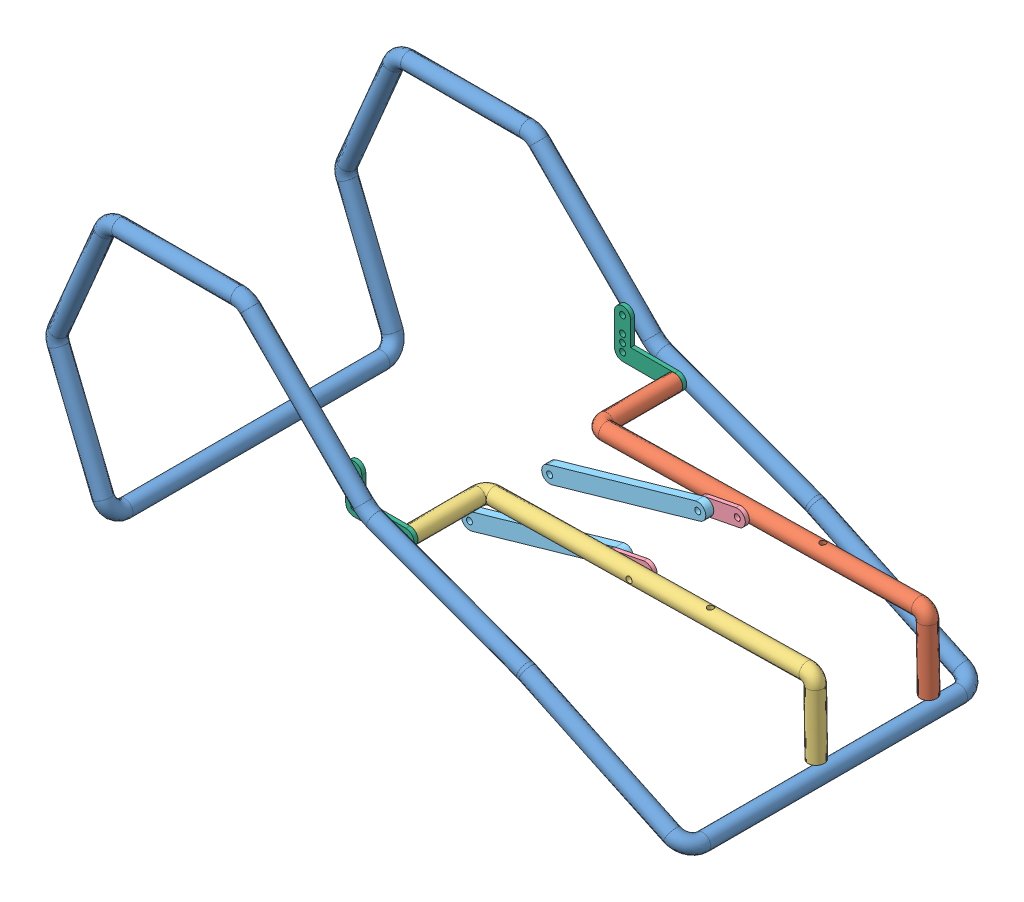
SolidWorks assembly Prototype, configuration Default. Lengths in mm.
Overall size (1087.11 431.8 482.6).
9 component instances, 6 part files, 26 mates.
Components (placement in the parent):
- Nubax Trio Frame-1: Nubax Trio Frame [Default] at (-437.8534 -203.7386 240.4024) size (1021.84 431.8 482.6)
- Support-2: Support [Default] at (19.3466 -9.1379 -197.7476) x (0.99987 0.016133 0) z (0 0 -1) size (546.1 127 133.35)
- Support 2-1: Support 2 [Default] at (19.3466 -9.1379 221.3524) x (0.99987 0.016133 0) z (0 0 1) size (546.1 127 133.35)
- Coupler-1: Coupler [Default] at (233.1407 -10.1249 81.6524) x (0.981686 0.190509 0) z (0 0 1) size (76.2 25.4 6.35)
- Coupler-2: Coupler [Default] at (233.1407 -10.1249 -64.3976) x (0.981686 0.190509 0) z (0 0 1) size (76.2 25.4 6.35)
- Rocker1-1: Rocker1 [Default] at (91.0226 -48.6174 -58.0476) x (0.27603 -0.961149 0) z (0 0 1) size (25.4 269.24 12.7)
- Rocker1-2: Rocker1 [Default] at (91.0226 -48.6174 68.9524) x (0.27603 -0.961149 0) z (0 0 1) size (25.4 269.24 12.7)
- Ground link support-1: Ground link support [Default] at (19.3466 -9.1379 221.3524) size (107.95 76.2 6.35)
- Ground link support-2: Ground link support [Default] at (19.3466 -9.1379 -204.0976) size (107.95 76.2 6.35)
Mates (geometry in assembly coordinates):
- Concentric2: concentric anti-aligned: cylinder of Nubax Trio Frame-1 through (19.3466 -9.1379 240.4024) axis (0 0 1) radius 4.7625; cylinder of Support-2 through (19.3466 -9.1379 -197.7476) axis (0 0 -1) radius 4.7625
- Concentric3: concentric aligned: cylinder of Nubax Trio Frame-1 through (19.3466 -9.1379 240.4024) axis (0 0 1) radius 4.7625; cylinder of Support 2-1 through (19.3466 -9.1379 221.3524) axis (0 0 1) radius 4.7625
- Coincident1: coincident aligned: plane of Support-2 through (541.8228 -115.0226 -77.0976) normal (0.016133 -0.99987 0); plane of Support 2-1 through (541.8228 -115.0226 100.7024) normal (0.016133 -0.99987 0)
- Concentric5: concentric aligned: cylinder of Support-2 through (258.0755 -5.286 -89.7976) axis (0 0 -1) radius 4.7625; cylinder of Coupler-2 through (258.0755 -5.286 -58.0476) axis (0 0 -1) radius 4.7625
- Tangent3: tangent anti-aligned: cylinder of Support 2-1 through (32.0449 -8.933 100.7024) axis (0.99987 0.016133 0) radius 12.7; plane of Coupler-1 through (208.2059 -14.9638 88.0024) normal (0 0 1)
- Tangent4: tangent anti-aligned: cylinder of Support-2 through (32.0449 -8.933 -77.0976) axis (0.99987 0.016133 0) radius 12.7; plane of Coupler-2 through (208.2059 -14.9638 -64.3976) normal (0 0 -1)
- Coincident2: coincident anti-aligned: plane of Coupler-2 through (208.2059 -14.9638 -58.0476) normal (0 0 1); plane of Rocker1-1 through (208.2059 -14.9638 -58.0476) normal (0 0 -1)
- Coincident3: coincident anti-aligned: plane of Coupler-1 through (208.2059 -14.9638 81.6524) normal (0 0 -1); plane of Rocker1-2 through (208.2059 -14.9638 81.6524) normal (0 0 1)
- Concentric8: concentric anti-aligned: circle of Support 2-1; cylinder of Ground link support-1 through (19.3466 -9.1379 227.7024) axis (0 0 -1) radius 4.7625
- Coincident6: coincident anti-aligned: plane of Support 2-1 through (19.3466 -9.1379 221.3524) normal (0 0 1); plane of Ground link support-1 through (19.3466 -9.1379 221.3524) normal (0 0 -1)
- Parallel1: parallel anti-aligned: plane of Ground link support-1 through (19.3466 -21.8379 227.7024) normal (0 -1 0); plane of assembly through (0 0 0) normal (0 1 0)
- Tangent5: tangent anti-aligned: cylinder of Nubax Trio Frame-1 through (220.3564 -83.223 240.4024) axis (-0.938299 0.345824 0) radius 12.7; plane of Ground link support-1 through (19.3466 -9.1379 227.7024) normal (0 0 1)
- Concentric9: concentric: cylinder of Rocker1-2 through (-63.2034 3.5621 81.6524) axis (0 0 -1) radius 4.7625; cylinder of Ground link support-1 through (-63.2034 -9.1379 227.7024) axis (0 0 -1) radius 4.7625
- Concentric10: concentric anti-aligned: cylinder of Nubax Trio Frame-1 through (19.3466 -9.1379 240.4024) axis (0 0 1) radius 4.7625; cylinder of Ground link support-2 through (19.3466 -9.1379 -197.7476) axis (0 0 -1) radius 4.7625
- Tangent6: tangent anti-aligned: cylinder of Nubax Trio Frame-1 through (-17.3086 4.3719 -216.7976) axis (0.938299 -0.345824 0) radius 12.7; plane of Ground link support-2 through (19.3466 -9.1379 -204.0976) normal (0 0 -1)
- Coincident7: coincident anti-aligned: plane of Support-2 through (19.3466 -9.1379 -197.7476) normal (0 0 -1); plane of Ground link support-2 through (19.3466 -9.1379 -197.7476) normal (0 0 1)
- Coincident9: coincident aligned: plane of Rocker1-1 through (204.7003 -2.7572 -45.3476) normal (-0.27603 0.961149 0); plane of Rocker1-2 through (204.7003 -2.7572 81.6524) normal (-0.27603 0.961149 0)
- Concentric11: concentric anti-aligned: cylinder of Support 2-1 through (258.0755 -5.286 221.3524) axis (0 0 1) radius 4.7625; cylinder of Coupler-1 through (258.0755 -5.286 88.0024) axis (0 0 -1) radius 4.7625
- Concentric12: concentric aligned: cylinder of Coupler-1 through (208.2059 -14.9638 88.0024) axis (0 0 -1) radius 4.7625; cylinder of Rocker1-2 through (208.2059 -14.9638 81.6524) axis (0 0 -1) radius 4.7625
- Concentric13: concentric aligned: cylinder of Coupler-2 through (208.2059 -14.9638 -58.0476) axis (0 0 -1) radius 4.7625; cylinder of Rocker1-1 through (208.2059 -14.9638 -45.3476) axis (0 0 -1) radius 4.7625
- Concentric14: concentric aligned: cylinder of Rocker1-2 through (-63.2034 -9.1379 81.6524) axis (0 0 -1) radius 4.7625; cylinder of Ground link support-1 through (-63.2034 -9.1379 227.7024) axis (0 0 -1) radius 4.7625
- Concentric15: concentric aligned: cylinder of Rocker1-1 through (-26.1607 -82.271 -45.3476) axis (0 0 -1) radius 4.7625; cylinder of Rocker1-2 through (-26.1607 -82.271 81.6524) axis (0 0 -1) radius 4.7625
- Parallel2: parallel anti-aligned: plane of Ground link support-2 through (19.3466 -21.8379 -197.7476) normal (0 -1 0); plane of assembly through (0 0 0) normal (0 1 0)
- Concentric16: concentric aligned: cylinder of Rocker1-2 through (-63.2034 3.5621 81.6524) axis (0 0 -1) radius 4.7625; cylinder of Ground link support-1 through (-63.2034 3.5621 227.7024) axis (0 0 -1) radius 4.7625
- Concentric17: concentric aligned: cylinder of Rocker1-2 through (-63.2034 16.2621 81.6524) axis (0 0 -1) radius 4.7625; cylinder of Ground link support-1 through (-63.2034 16.2621 227.7024) axis (0 0 -1) radius 4.7625
- Concentric18: concentric: cylinder of Rocker1-2 through (-63.2034 41.6621 81.6524) axis (0 0 -1) radius 4.7625; cylinder of Ground link support-1 through (-63.2034 41.6621 227.7024) axis (0 0 -1) radius 4.7625
